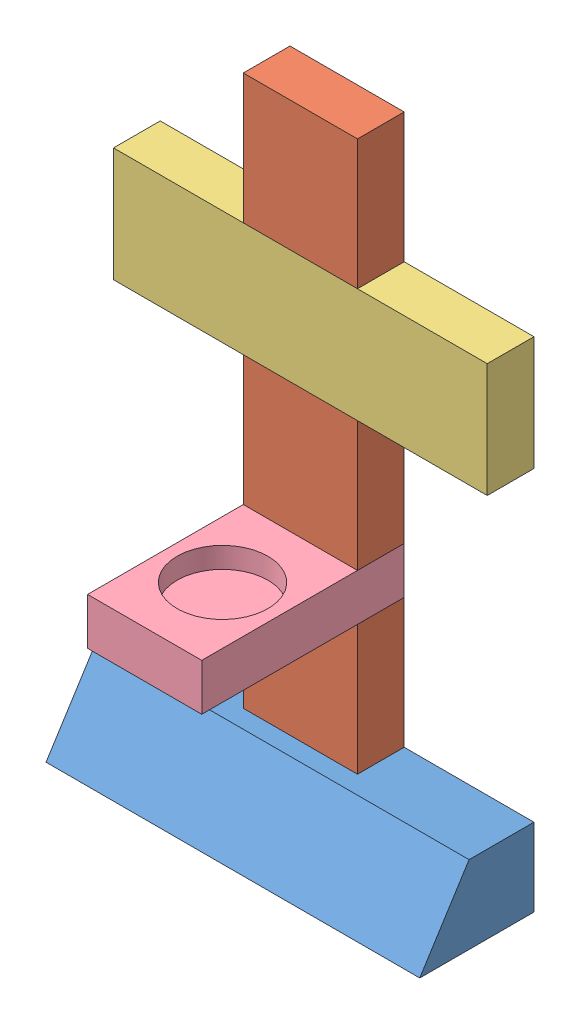
SolidWorks assembly Assem1, configuration Default. Lengths in mm.
Overall size (144 242 78).
4 component instances, 4 part files, 9 mates.
Components (placement in the parent):
- Base-1: Base [Default] at origin size (144 30 44)
- Upright-1: Upright [Default] at (-22 0 9) size (44 242 18)
- Cross Rail-1: Cross Rail [Default] at (0 170 9) x (1 0 0) z (0 -1 0) size (144 18 44)
- Center Piece-1: Center Piece [Default] at (0 89 0) size (44 18 78)
Mates (geometry in assembly coordinates):
- Coincident1: coincident anti-aligned: plane of Base-1 through (-22 0 9) normal (0 0 -1); plane of Upright-1 through (-22 30 9) normal (0 0 1)
- Coincident2: coincident aligned: plane of Base-1 through (72 0 0) normal (0 -1 0); plane of Upright-1 through (-22 0 18) normal (0 -1 0)
- Coincident3: coincident anti-aligned: plane of Base-1 through (-22 0 0) normal (1 0 0); plane of Upright-1 through (-22 0 18) normal (-1 0 0)
- Coincident4: coincident: plane of Upright-1 through (-22 148 9) normal (0 0 1); plane of Cross Rail-1 through (-143.9718 148 9) normal (0 0 -1)
- Coincident5: coincident: plane of Upright-1 through (-22 148 9) normal (0 1 0); plane of Cross Rail-1 through (-49.9718 148 18) normal (0 -1 0)
- Coincident6: coincident anti-aligned: plane of Upright-1 through (-22 0 18) normal (-1 0 0); plane of Cross Rail-1 through (-22 192 9) normal (1 0 0)
- Coincident7: coincident: plane of Upright-1 through (-7 98 0) normal (-1 0 0); plane of Center Piece-1 through (-7 80 0) normal (1 0 0)
- Coincident8: coincident: plane of Upright-1 through (-22 242 18) normal (0 0 1); plane of Center Piece-1 through (-7 80 18) normal (0 0 -1)
- Coincident9: coincident anti-aligned: plane of Upright-1 through (-22 98 0) normal (0 -1 0); plane of Center Piece-1 through (22 98 78) normal (0 1 0)
